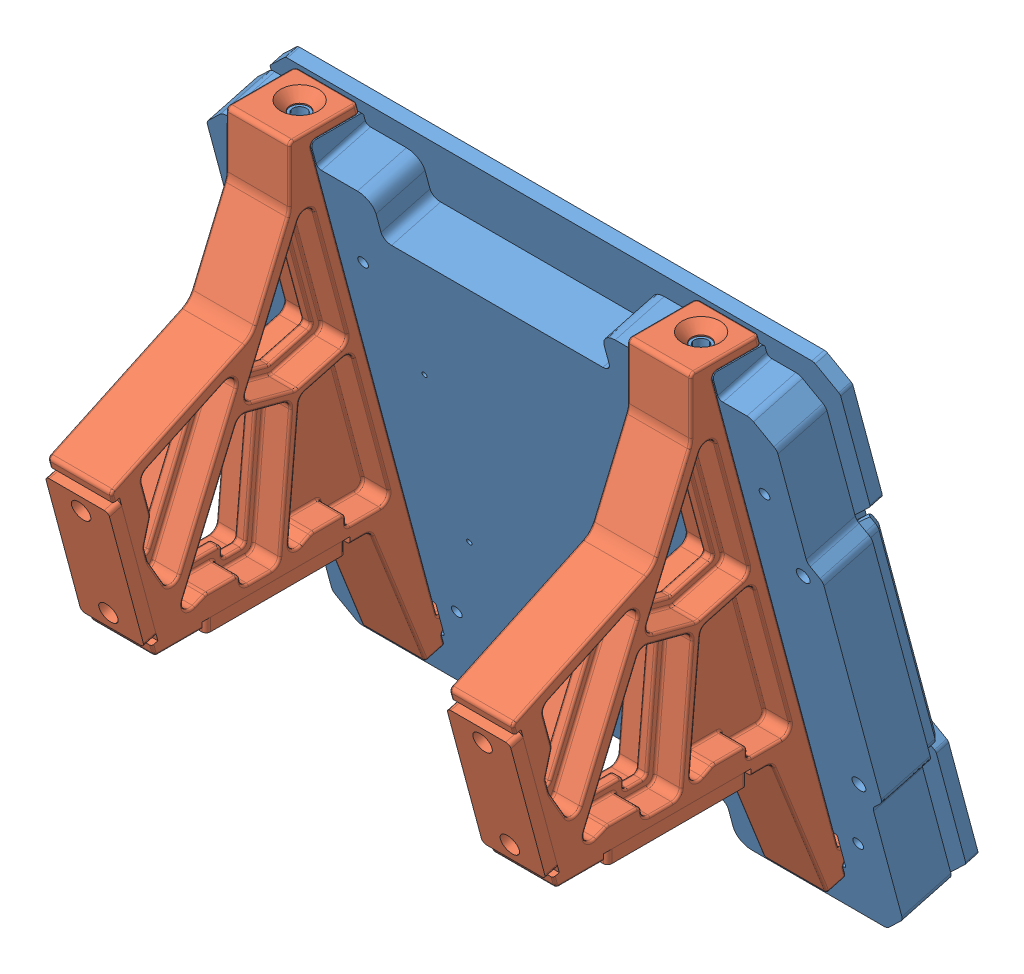
SolidWorks assembly 装配体4, configuration 默认. Lengths in mm.
Overall size (141 141.2 111.81).
3 component instances, 2 part files, 6 mates.
Components (placement in the parent):
- 小装甲-1: 小装甲 [默认] at (-1.6061 -73.3569 212.2779) size (141 126.74 52.99)
- 装甲支撑架（B）-1: 装甲支撑架（B） [默认] at (-49.1061 -39.0247 199.2187) x (1 0 0) z (0 -0.258819 0.965926) size (15.02 127.12 71.15)
- 装甲支撑架（B）-2: 装甲支撑架（B） [默认] at (45.8939 -39.0247 199.2187) x (1 0 0) z (0 -0.258819 0.965926) size (15.02 127.12 71.15)
Mates (geometry in assembly coordinates):
- 重合1: coincident: plane of 小装甲-1 through (-1.6061 -3.8049 150.0141) normal (0 -0.258819 0.965926); plane of 装甲支撑架（B）-1 through (-56.6061 62.5691 167.7989) normal (0 0.258819 -0.965926)
- 重合2: coincident: plane of 小装甲-1 through (-41.6061 -3.8049 150.0141) normal (1 0 0); plane of 装甲支撑架（B）-1 through (-41.6061 -24.3642 144.5052) normal (1 0 0)
- 重合3: coincident anti-aligned: plane of 小装甲-1 through (-41.6061 62.5691 167.7989) normal (0 1 0); plane of 装甲支撑架（B）-1 through (-23.9209 62.5691 155.8932) normal (0 -1 0)
- 重合4: coincident: plane of 小装甲-1 through (-1.6061 -3.8049 150.0141) normal (0 -0.258819 0.965926); plane of 装甲支撑架（B）-2 through (38.3939 62.5691 167.7989) normal (0 0.258819 -0.965926)
- 重合5: coincident: plane of 小装甲-1 through (38.3939 62.5691 167.7989) normal (0 1 0); plane of 装甲支撑架（B）-2 through (71.0791 62.5691 155.8932) normal (0 -1 0)
- 重合6: coincident aligned: plane of 小装甲-1 through (38.3939 -3.8049 150.0141) normal (-1 0 0); plane of 装甲支撑架（B）-2 through (38.3939 -24.3642 144.5052) normal (-1 0 0)
